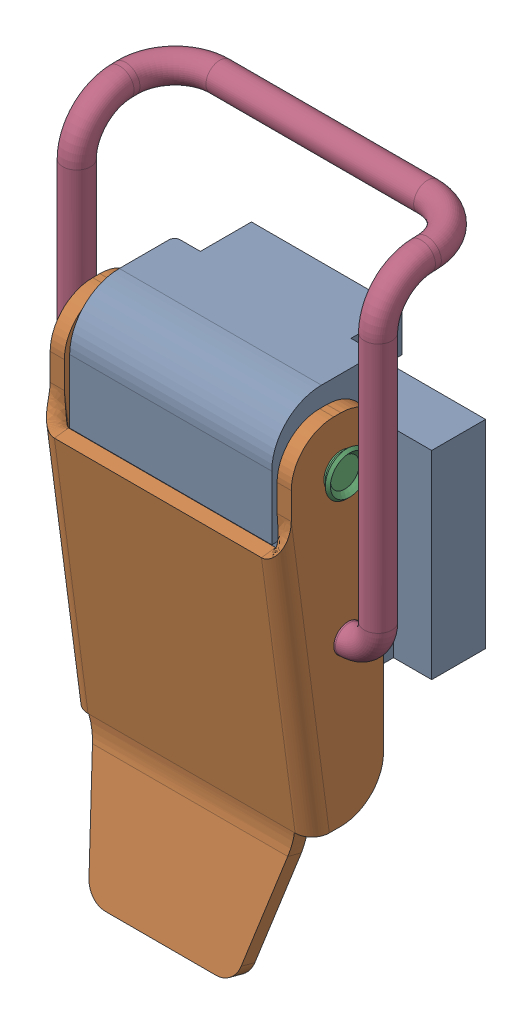
SolidWorks assembly WQ-50L-01_DEFAULT, configuration Default. Lengths in mm.
Overall size (23.23 44.9 15.28).
4 component instances, 4 part files, 0 mates.
Components (placement in the parent):
- BASE^WQ-50L-01-1: BASE^WQ-50L-01 [Default] at origin size (16 21 14.2)
- FRONT^WQ-50L-01_default-1: FRONT^WQ-50L-01_default [Default] at (0 12.75 15.1) size (17.35 34.89 7.58)
- PIN^WQ-50L-01-1: PIN^WQ-50L-01 [Default] at (0 16.5 10.7) size (18.22 3.75 3.75)
- LOOP^WQ-50L-01-1: LOOP^WQ-50L-01 [Default] at (0 6 10.2) x (1 0 0) z (0 0 -1) size (23.23 25.83 8.77)
